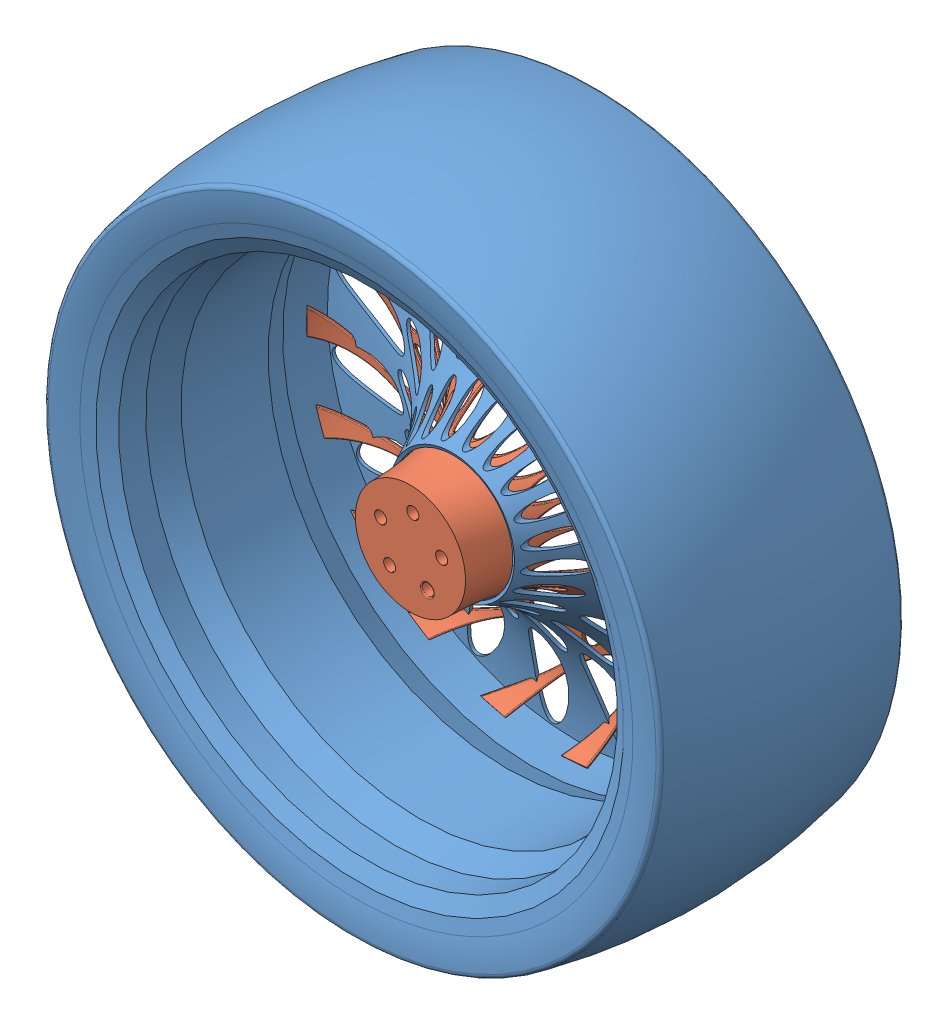
SolidWorks assembly Assem1, configuration Default. Lengths in mm.
Overall size (327.93 327.93 124.85).
3 component instances, 3 part files, 3 mates.
Components (placement in the parent):
- Part1 wheel-1: Part1 wheel [Default] at (82.3116 155.2734 199.9039) x (0.997881 0.065073 0) z (0 0 1) size (308.51 308.51 117.12)
- Part2 wheel-1: Part2 wheel [Default] at (82.3116 155.2734 199.9442) x (0.378507 0.925598 0) z (0 0 1) size (247.23 247.45 96.87)
- Part3 SYMBOL-1: Part3 SYMBOL [Default] at (82.3116 155.2734 199.9442) x (0.065073 -0.997881 0) z (0.997881 0.065073 0) size (48.6 5 48.6)
Mates (geometry in assembly coordinates):
- Concentric1: concentric anti-aligned: circle of Part1 wheel-1; circle of Part2 wheel-1
- Parallel1: parallel aligned: cylinder of Part1 wheel-1 through (82.3116 155.2734 199.9039) axis (0 0 1) radius 120; cone of Part2 wheel-1 through (82.3116 155.2734 149.9442) axis (0 0 1)
- ProfileCenter1: profile center aligned: plane of Part3 SYMBOL-1 through (82.3116 155.2734 199.9442) normal (0 0 1); plane of Part2 wheel-1 through (82.3116 155.2734 199.9442) normal (0 0 -1)
